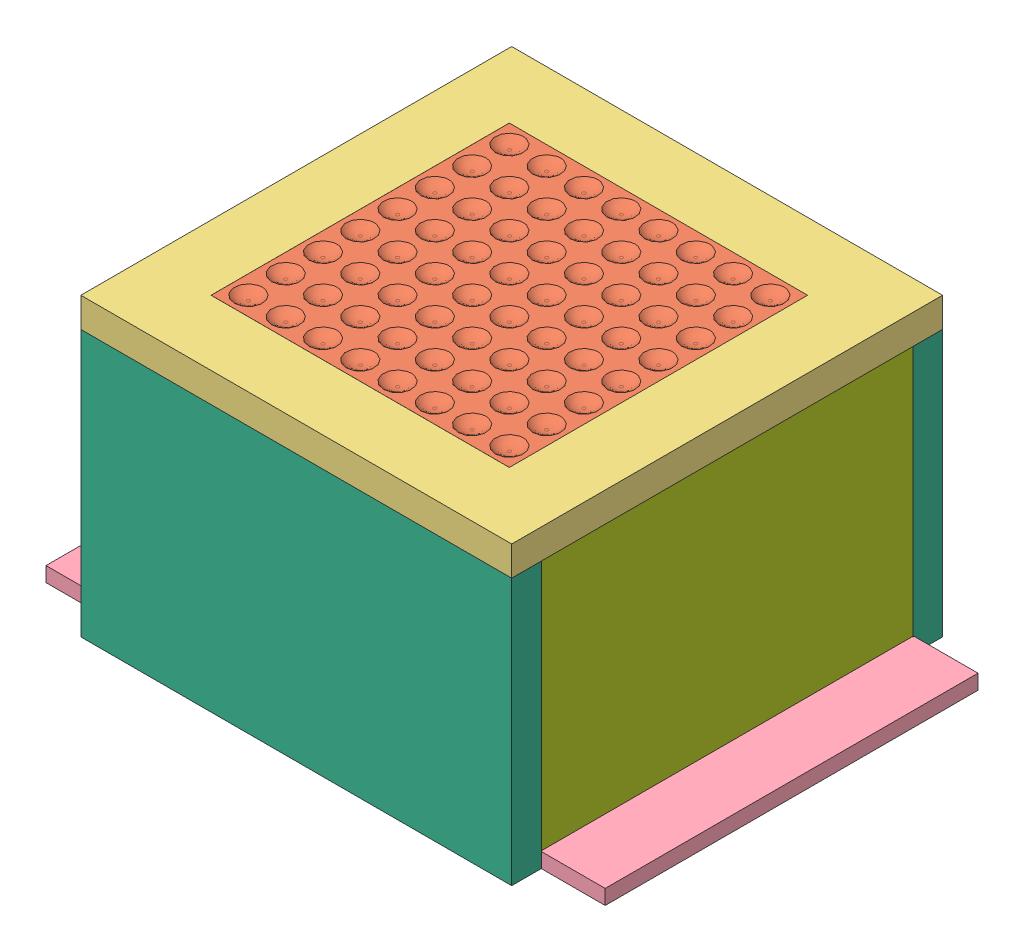
SolidWorks assembly cube, configuration Default. Lengths in mm.
Overall size (60 36.75 46.23).
11 component instances, 7 part files, 22 mates.
Components (placement in the parent):
- ledmatrixbackpack-1: ledmatrixbackpack [Default] at (-2.4215 -0.1769 -1.3195) size (39.69 12.76 33.34)
  - LEDbackpack-1: LEDbackpack [Default] at (14.4644 16.8017 31.6864) size (39.69 4.76 33.34)
  - LED Matrix-1: LED Matrix [?] at (14.2971 25.5642 31.6526) x (-1 0 0) z (0 0 -1) size (32 12.5 32)
- cubetop-1: cubetop [Default] at (-261.361 26.2123 338.6099) size (46.23 3.17 46.23)
- cubebottom-1: cubebottom [Default] at (-5.8761 29.2621 78.9283) x (1 0 0) z (0 0 -1) size (60 6.59 40)
  - protoboard-1: protoboard [Default] at (17.8486 30.0373 48.7812) size (60 1.59 40)
  - cubebottompins-1: cubebottompins [Default] at (18.9924 31.6248 49.6374) size (14.29 5 14.29)
- cubeside1-1: cubeside1 [Default] at (12.0005 11.9248 50.1471) size (46.23 28.57 3.17)
- cubeside1-2: cubeside1 [Default] at (12.0005 11.9248 7.0941) size (46.23 28.57 3.17)
- cubeside2-1: cubeside2 [Default] at (31.9395 12.7503 30.2081) x (0 0 -1) z (1 0 0) size (39.88 26.92 3.17)
- cubeside2-2: cubeside2 [Default] at (-7.9385 12.7503 30.2081) x (0 0 1) z (-1 0 0) size (39.88 26.92 3.17)
Mates (geometry in assembly coordinates):
- Coincident2: coincident: plane of ledmatrixbackpack-1/LED Matrix-1 through (-4.1245 29.3873 46.3331) normal (0 1 0); plane of cubetop-1 through (-261.361 29.3873 338.6099) normal (0 1 0)
- Coincident3: coincident aligned: line of ledmatrixbackpack-1/LED Matrix-1 through (27.8755 29.3873 14.3331) axis (-1 0 0); line of cubetop-1 through (27.8755 29.3873 14.3331) axis (-1 0 0)
- Coincident4: coincident aligned: line of ledmatrixbackpack-1/LED Matrix-1 through (27.8755 29.3873 46.3331) axis (0 0 -1); line of cubetop-1 through (27.8755 29.3873 46.3371) axis (0 0 -1)
- Coincident5: coincident anti-aligned: plane of cubetop-1 through (-261.361 26.2123 338.6099) normal (0 -1 0); plane of cubeside1-1 through (-11.1135 26.2123 53.3221) normal (0 1 0)
- Coincident6: coincident anti-aligned: line of cubetop-1 through (-11.1135 26.2123 53.3221) axis (1 0 0); line of cubeside1-1 through (35.1145 26.2123 53.3221) axis (-1 0 0)
- Coincident7: coincident anti-aligned: line of cubetop-1 through (-11.1135 26.2123 7.0941) axis (0 0 1); line of cubeside1-1 through (-11.1135 26.2123 53.3221) axis (0 0 -1)
- Coincident8: coincident anti-aligned: plane of cubebottom-1/protoboard-1 through (-18.5355 -2.3627 50.1471) normal (0 0 1); plane of cubeside1-1 through (12.0005 11.9248 50.1471) normal (0 0 -1)
- Coincident9: coincident anti-aligned: line of cubebottom-1/protoboard-1 through (41.4645 -2.3627 50.1471) axis (-1 0 0); line of cubeside1-1 through (-11.1135 -2.3627 50.1471) axis (1 0 0)
- Coincident10: coincident anti-aligned: plane of cubetop-1 through (-261.361 26.2123 338.6099) normal (0 -1 0); plane of cubeside1-2 through (-11.1135 26.2123 10.2691) normal (0 1 0)
- Coincident11: coincident aligned: line of cubetop-1 through (35.1145 26.2123 53.3221) axis (0 0 -1); line of cubeside1-2 through (35.1145 26.2123 10.2691) axis (0 0 -1)
- Coincident12: coincident aligned: line of cubetop-1 through (35.1145 26.2123 7.0941) axis (-1 0 0); line of cubeside1-2 through (35.1145 26.2123 7.0941) axis (-1 0 0)
- Parallel1: parallel aligned: line of cubebottom-1/protoboard-1 through (-18.5355 -2.3627 10.1471) axis (1 0 0); line of cubeside1-2 through (-11.1135 -2.3627 10.2691) axis (1 0 0)
- Coincident14: coincident anti-aligned: plane of cubeside1-2 through (12.0005 11.9248 10.2691) normal (0 0 1); plane of cubeside2-1 through (35.1145 -0.7117 10.2691) normal (0 0 -1)
- Coincident15: coincident anti-aligned: plane of cubetop-1 through (-261.361 26.2123 338.6099) normal (0 -1 0); plane of cubeside2-1 through (35.1145 26.2123 50.1471) normal (0 1 0)
- Coincident16: coincident aligned: line of cubeside1-2 through (35.1145 -2.3627 10.2691) axis (0 1 0); line of cubeside2-1 through (35.1145 -0.7117 10.2691) axis (0 1 0)
- Coincident17: coincident anti-aligned: line of cubeside1-1 through (35.1145 -2.3627 50.1471) axis (0 1 0); line of cubeside2-1 through (35.1145 26.2123 50.1471) axis (0 -1 0)
- Parallel2: parallel anti-aligned: plane of cubebottom-1/protoboard-1 through (11.4645 -0.7752 30.1471) normal (0 1 0); plane of cubeside2-1 through (35.1145 -0.7117 50.1471) normal (0 -1 0)
- Coincident19: coincident anti-aligned: plane of cubetop-1 through (-261.361 26.2123 338.6099) normal (0 -1 0); plane of cubeside2-2 through (-11.1135 26.2123 10.2691) normal (0 1 0)
- Coincident20: coincident anti-aligned: plane of cubeside1-2 through (12.0005 11.9248 10.2691) normal (0 0 1); plane of cubeside2-2 through (-11.1135 -0.7117 10.2691) normal (0 0 -1)
- Coincident21: coincident anti-aligned: line of cubeside1-1 through (-11.1135 26.2123 50.1471) axis (0 -1 0); line of cubeside2-2 through (-11.1135 -0.7117 50.1471) axis (0 1 0)
- Coincident22: coincident aligned: line of cubeside1-2 through (-11.1135 26.2123 10.2691) axis (0 -1 0); line of cubeside2-2 through (-11.1135 26.2123 10.2691) axis (0 -1 0)
- Distance1: distance = 6.858 mm aligned: plane of cubebottom-1/protoboard-1 through (41.9725 -2.3627 10.1471) normal (1 0 0); plane of cubeside2-1 through (35.1145 12.7503 30.2081) normal (1 0 0)
